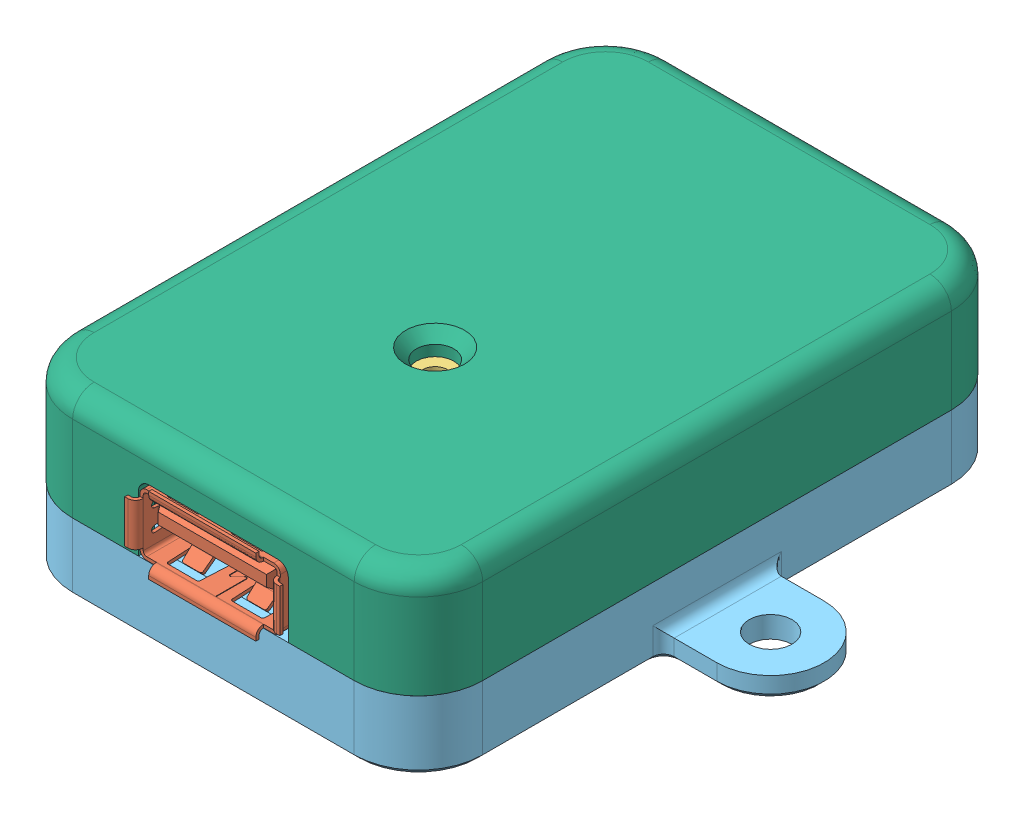
SolidWorks assembly MCU_assem, configuration Default. Lengths in mm.
Overall size (58.29 19.5 56.77).
6 component instances, 6 part files, 17 mates.
Components (placement in the parent):
- MCU_pcb-1: MCU_pcb [Default] at (2.7151 19.0352 49.2946) size (34.29 3.22 48.26)
- USB-A-1: USB-A [Default] at (19.8234 27.5552 41.9997) x (1 0 0) z (0 1 0) size (15.09 13.8 10.75)
- Buzzer-1: Buzzer [Default] at (19.8234 20.6552 34.0546) size (12 8.5 12)
- ARDUINO PRO MICRO-1: ARDUINO PRO MICRO [Default] at (6.5251 21.9252 25.1746) size (34.59 4.25 17.78)
- Case_bottom-1: Case_bottom [Default] at (2.7151 19.0352 49.2946) x (-1 0 0) z (0 -1 0) size (58.29 55.26 8)
- Case_top-1: Case_top [Default] at (2.7151 21.5352 49.2946) x (1 0 0) z (0 1 0) size (38.29 55.26 13.75)
Mates (geometry in assembly coordinates):
- Coincident1: coincident: plane of MCU_pcb-1 through (2.7151 20.6552 49.2946) normal (0 1 0); plane of USB-A-1 through (17.346 20.6552 41.9997) normal (0 -1 0)
- Distance1: distance = 0.015 mm: plane of USB-A-1 through (13.6234 20.6552 49.2797) normal (0 0 1); plane of MCU_pcb-1 through (2.7151 20.6552 49.2946) normal (0 0 1)
- Distance2: distance = 10.6317 mm: plane of USB-A-1 through (26.3734 20.5774 41.9997) normal (1 0 0); plane of MCU_pcb-1 through (37.0051 20.6552 49.2946) normal (1 0 0)
- Coincident4: coincident: plane of MCU_pcb-1 through (2.7151 20.6552 49.2946) normal (0 1 0); plane of Buzzer-1 through (19.8234 20.6552 34.0546) normal (0 -1 0)
- Distance3: distance = 15.24 mm: cylinder of Buzzer-1 through (19.8234 26.1552 34.0546) axis (0 1 0) radius 1.15; line of MCU_pcb-1 through (6.7151 20.6552 49.2946) axis (1 0 0)
- Coincident6: coincident: plane of USB-A-1 through (19.8234 27.5552 41.9997) normal (1 0 0); plane of Buzzer-1 through (19.8234 20.6552 34.0546) normal (1 0 0)
- Distance4: distance = 1.27 mm: plane of ARDUINO PRO MICRO-1 through (6.5251 21.9252 25.1746) normal (0 -1 0); plane of MCU_pcb-1 through (2.7151 20.6552 49.2946) normal (0 1 0)
- InPlace1: in place: plane of MCU_pcb-1 through (2.7151 19.0352 49.2946) normal (0 -1 0); plane of ? through (0 19.0352 0) normal (0 -1 0); moOrthogonalPlaneRef_w of MCU_pcb-1 through (2.7151 19.0352 49.2946) normal (0 -1 0); plane of ? through (0 19.0352 0) normal (0 0 -1); plane of MCU_pcb-1 through (2.7151 19.0352 49.2946) normal (0 -1 0); plane of ? through (0 19.0352 0) normal (-1 0 0); plane of MCU_pcb-1 through (2.7151 19.0352 49.2946) normal (0 -1 0); unknown of Case_bottom-1
- Coincident8: coincident: plane of MCU_pcb-1; plane of Case_bottom-1
- Coincident9: coincident: moOrthogonalPlaneRef_w of MCU_pcb-1 through (2.7151 19.0352 49.2946) normal (0 0 -1); plane of Case_bottom-1 through (2.7151 19.0352 49.2946) normal (0 0 -1)
- Coincident10: coincident: moOrthogonalPlaneRef_w of MCU_pcb-1 through (2.7151 19.0352 49.2946) normal (1 0 0); plane of Case_bottom-1 through (2.7151 19.0352 49.2946) normal (-1 0 0)
- Distance5: distance = 16.5 mm: plane of Buzzer-1 through (19.8234 20.6552 34.0546) normal (0 0 1); line of ARDUINO PRO MICRO-1 through (16.8154 24.5452 17.5546) axis (0 -1 0)
- Coincident12: coincident: plane of MCU_pcb-1 through (2.7151 20.6552 49.2946) normal (-1 0 0); plane of ARDUINO PRO MICRO-1 through (2.7151 23.5252 8.6646) normal (-1 0 0)
- InPlace2: in place: plane of Case_bottom-1 through (33.0051 21.5352 5.0346) normal (0 1 0); plane of ? through (0 21.5352 0) normal (0 1 0); plane of Case_bottom-1 through (33.0051 21.5352 5.0346) normal (0 1 0); plane of ? through (0 21.5352 0) normal (0 0 -1); plane of Case_bottom-1 through (33.0051 21.5352 5.0346) normal (0 1 0); plane of ? through (0 21.5352 0) normal (1 0 0); plane of Case_bottom-1 through (33.0051 21.5352 5.0346) normal (0 1 0); unknown of Case_top-1
- Coincident13: coincident: plane of Case_bottom-1; plane of Case_top-1
- Coincident14: coincident: moOrthogonalPlaneRef_w of Case_bottom-1 through (2.7151 21.5352 49.2946) normal (0 0 -1); plane of Case_top-1 through (2.7151 21.5352 49.2946) normal (0 0 -1)
- Coincident15: coincident: moOrthogonalPlaneRef_w of Case_bottom-1 through (2.7151 21.5352 49.2946) normal (-1 0 0); plane of Case_top-1 through (2.7151 21.5352 49.2946) normal (1 0 0)
